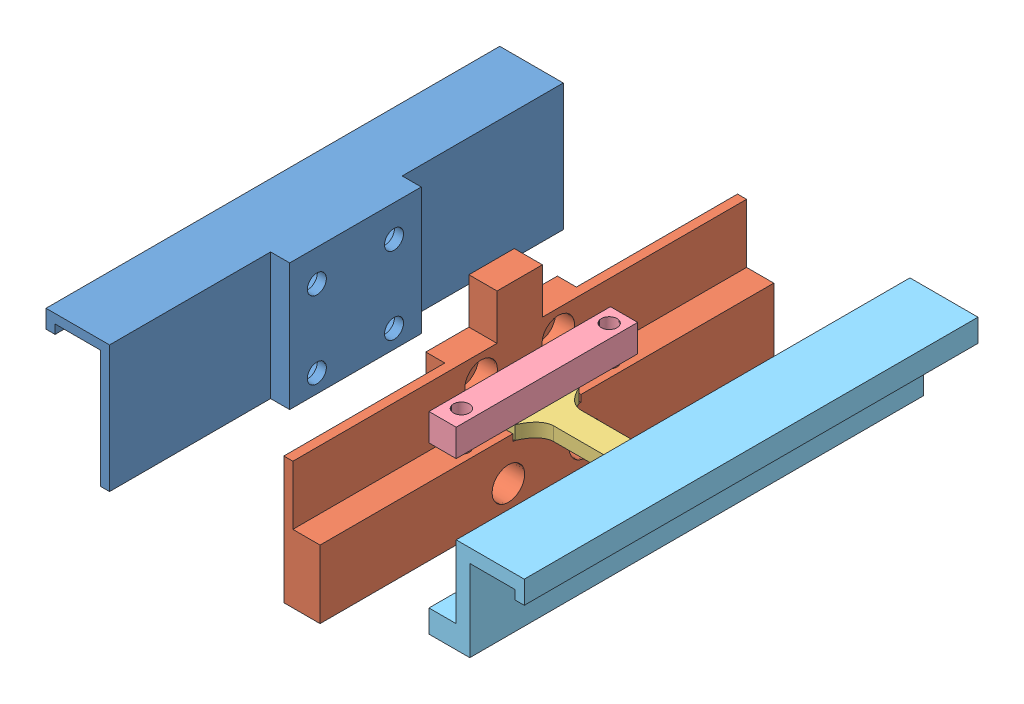
SolidWorks assembly Assem1, configuration Default. Lengths in mm.
Overall size (105.4 38 100).
6 component instances, 5 part files, 15 mates.
Components (placement in the parent):
- drzalo_leva-1: drzalo_leva [Default] at (-58.901 2.9814 71.0746) size (18.2 28 100)
- drzalo_leva_srednja-1: drzalo_leva_srednja [Default] at (-32.701 2.9814 71.0746) size (12.2 38 100)
- tensile_test_sample-1: tensile_test_sample [Default] at (-69.001 13.4814 21.0746) size (36 3 14.13)
- drzalo_pokrov-1: drzalo_pokrov [Default] at (-16.501 17.4814 1.0746) x (0 0 1) z (-1 0 0) size (40 6 6)
- drzalo_desna-1: drzalo_desna [Default] at (19.499 2.9814 71.0746) size (21 21 100)
- drzalo_pokrov-2: drzalo_pokrov [Default] at (19.499 17.4814 41.0746) x (0 0 -1) z (1 0 0) size (40 6 6)
Mates (geometry in assembly coordinates):
- Concentric4: concentric aligned: cylinder of drzalo_leva-1 through (-54.701 23.9814 12.5746) axis (-1 0 0) radius 3.6; cylinder of drzalo_leva_srednja-1 through (-8.701 23.9814 12.5746) axis (-1 0 0) radius 2.1
- Concentric5: concentric anti-aligned: cylinder of drzalo_leva-1 through (-70.901 6.9814 29.5746) axis (1 0 0) radius 2.1; cylinder of drzalo_leva_srednja-1 through (-8.701 6.9814 29.5746) axis (-1 0 0) radius 2.1
- Distance1: distance = 30 mm anti-aligned: plane of drzalo_leva-1 through (-52.701 2.9814 71.0746) normal (1 0 0); plane of drzalo_leva_srednja-1 through (-22.701 2.9814 71.0746) normal (-1 0 0)
- Coincident2: coincident anti-aligned: plane of drzalo_leva_srednja-1 through (-117.3425 14.4814 28.5746) normal (0 1 0); plane of tensile_test_sample-1 through (-15.001 14.4814 6.0746) normal (0 -1 0)
- Coincident3: coincident anti-aligned: plane of drzalo_leva_srednja-1 through (-16.501 2.9814 71.0746) normal (1 0 0); plane of tensile_test_sample-1 through (-16.501 17.4814 21.0746) normal (-1 0 0)
- Width1: width aligned: plane of tensile_test_sample-1 through (-16.501 17.4814 28.1374) normal (0 0 1); plane of drzalo_leva_srednja-1 through (-16.501 17.4814 14.0119) normal (0 0 -1); plane of tensile_test_sample-1 through (-117.3425 15.9814 13.5746) normal (0 0 1); plane of drzalo_leva_srednja-1 through (-117.3425 15.9814 28.5746) normal (0 0 -1)
- Coincident4: coincident anti-aligned: plane of drzalo_leva_srednja-1 through (-16.501 2.9814 71.0746) normal (1 0 0); plane of drzalo_pokrov-1 through (-16.501 27.4814 1.0746) normal (-1 0 0)
- Coincident5: coincident anti-aligned: plane of tensile_test_sample-1 through (-15.001 17.4814 6.0746) normal (0 1 0); plane of drzalo_pokrov-1 through (-16.501 17.4814 1.0746) normal (0 -1 0)
- Width2: width aligned: plane of drzalo_pokrov-1 through (-16.501 27.4814 41.0746) normal (0 0 1); plane of drzalo_leva_srednja-1 through (-16.501 27.4814 1.0746) normal (0 0 -1); plane of drzalo_pokrov-1 through (-22.701 2.9814 71.0746) normal (0 0 1); plane of drzalo_leva_srednja-1 through (-22.701 2.9814 -28.9254) normal (0 0 -1)
- Coincident7: coincident anti-aligned: plane of tensile_test_sample-1 through (19.499 17.4814 21.0746) normal (1 0 0); plane of drzalo_desna-1 through (19.499 2.9814 71.0746) normal (-1 0 0)
- Coincident8: coincident aligned: plane of drzalo_leva-1 through (-68.901 28.9814 -43.4856) normal (0 -1 0); plane of drzalo_desna-1 through (33.499 28.9814 -43.4856) normal (0 -1 0)
- Coincident9: coincident aligned: plane of drzalo_leva-1 through (-56.901 2.9814 71.0746) normal (0 0 1); plane of drzalo_desna-1 through (21.499 2.9814 71.0746) normal (0 0 1)
- Coincident10: coincident anti-aligned: plane of drzalo_desna-1 through (19.499 2.9814 71.0746) normal (-1 0 0); plane of drzalo_pokrov-2 through (19.499 27.4814 41.0746) normal (1 0 0)
- Width3: width aligned: plane of drzalo_pokrov-2 through (19.499 27.4814 41.0746) normal (0 0 1); plane of drzalo_desna-1 through (19.499 27.4814 1.0746) normal (0 0 -1); plane of drzalo_pokrov-2 through (21.499 2.9814 71.0746) normal (0 0 1); plane of drzalo_desna-1 through (21.499 2.9814 -28.9254) normal (0 0 -1)
- Coincident11: coincident anti-aligned: plane of tensile_test_sample-1 through (-15.001 17.4814 6.0746) normal (0 1 0); plane of drzalo_pokrov-2 through (19.499 17.4814 41.0746) normal (0 -1 0)
